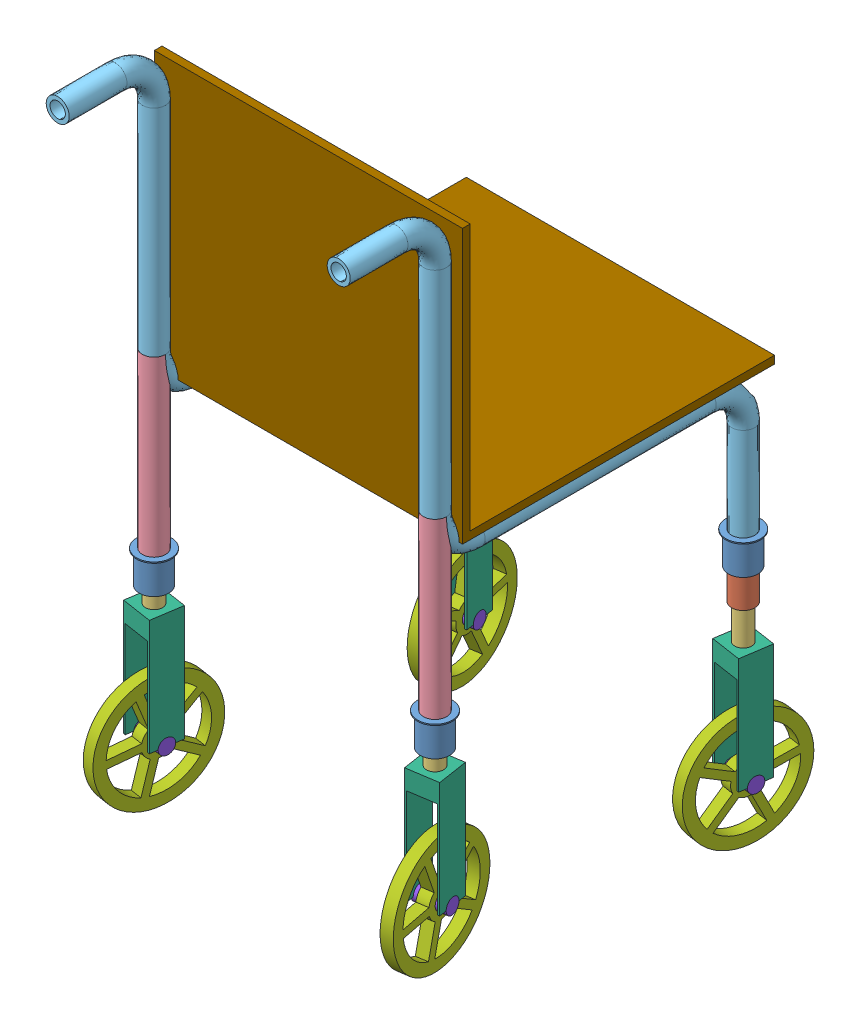
SolidWorks assembly telescope_copy_1, configuration Default. Lengths in mm.
Overall size (854.56 1888.19 1253.25).
33 component instances, 9 part files, 36 mates.
Components (placement in the parent):
- Part1-1: Part1 [Default] at (-1335.3167 235.5102 -102.0861) x (0 -1 0) z (-0.568138 0 -0.822933) size (83 90 90)
- Part2-1: Part2 [Default] at (-1335.3167 243.7286 -102.0861) x (0 -1 0) z (-0.866706 0 0.498819) size (83 70 70)
- Part3-1: Part3 [Default] at (-1335.3167 362.4799 -102.0861) x (0 -1 0) z (0.973036 0 -0.230654) size (120 54 54)
- fra-1: fra [Default] at (-1335.3167 757.6458 697.9139) size (60 450 60)
- frame-1: frame [Default] at (-1335.3167 657.4677 697.9139) size (60 1140 1080)
- Part3-2: Part3 [Default] at (-1335.3167 504.1743 697.9139) x (0 -1 0) z (-0.936287 0 0.351235) size (120 54 54)
- Part2-2: Part2 [Default] at (-1335.3167 310.8642 697.9139) x (0 -1 0) z (-0.866706 0 0.498819) size (83 70 70)
- Part1-2: Part1 [Default] at (-1335.3167 227.6458 697.9139) x (0 -1 0) z (-0.568138 0 -0.822933) size (83 90 90)
- rev-1: rev [Default] at (-1295.7832 34.1829 691.8227) x (-0.988337 0 0.152282) z (-0.152282 0 -0.988337) size (80 300 80)
- rev-2: rev [Default] at (-1295.7679 -87.4278 -96.0946) x (-0.988718 0 -0.149786) z (0.149786 0 -0.988718) size (80 300 80)
- wheel_fr-1: wheel_fr [Default] at (-1350.1417 -115.8171 700.1982) x (0.988337 0 -0.152282) z (0.095682 0.777955 0.620992) size (30 300 300)
- wheel_fr-2: wheel_fr [Default] at (-1320.4859 -237.4278 -99.8393) x (-0.988718 0 -0.149786) z (0.071254 0.879605 -0.470339) size (30 300 300)
- pin-1: pin [Default] at (-1335.3167 -115.8171 697.9139) x (0.988337 0 -0.152282) z (0.152282 0 0.988337) size (40 40 40)
- pin-2: pin [Default] at (-1374.8502 -115.8171 704.0052) x (0.988337 0 -0.152282) z (0.152282 0 0.988337) size (40 40 40)
- pin-3: pin [Default] at (-1335.3167 -237.4278 -102.0861) x (-0.988718 0 -0.149786) z (0.149786 0 -0.988718) size (40 40 40)
- pin-4: pin [Default] at (-1295.7679 -237.4278 -96.0946) x (-0.988718 0 -0.149786) z (0.130765 -0.487692 -0.863167) size (40 40 40)
- wheel_fr-3: wheel_fr [Default] at (-2049.8583 -115.8171 700.1982) x (-0.988337 0 -0.152282) z (0.095682 -0.777955 -0.620992) size (30 300 300)
- pin-5: pin [Default] at (-2064.6833 -115.8171 697.9139) x (-0.988337 0 -0.152282) z (0.152282 0 -0.988337) size (40 40 40)
- rev-3: rev [Default] at (-2104.2168 34.1829 691.8227) x (0.988337 0 0.152282) z (-0.152282 0 0.988337) size (80 300 80)
- pin-6: pin [Default] at (-2025.1498 -115.8171 704.0052) x (-0.988337 0 -0.152282) z (0.152282 0 -0.988337) size (40 40 40)
- Part3-3: Part3 [Default] at (-2064.6833 504.1743 697.9139) x (0 -1 0) z (-0.936287 0 -0.351235) size (120 54 54)
- Part2-3: Part2 [Default] at (-2064.6833 310.8642 697.9139) x (0 -1 0) z (-0.866706 0 -0.498819) size (83 70 70)
- Part1-3: Part1 [Default] at (-2064.6833 227.6458 697.9139) x (0 -1 0) z (-0.568138 0 0.822933) size (83 90 90)
- wheel_fr-4: wheel_fr [Default] at (-2079.5141 -237.4278 -99.8393) x (0.988718 0 -0.149786) z (0.071254 -0.879605 0.470339) size (30 300 300)
- pin-7: pin [Default] at (-2064.6833 -237.4278 -102.0861) x (0.988718 0 -0.149786) z (0.149786 0 0.988718) size (40 40 40)
- rev-4: rev [Default] at (-2104.2321 -87.4278 -96.0946) x (0.988718 0 -0.149786) z (0.149786 0 0.988718) size (80 300 80)
- pin-8: pin [Default] at (-2104.2321 -237.4278 -96.0946) x (0.988718 0 -0.149786) z (0.130765 0.487692 0.863167) size (40 40 40)
- Part3-4: Part3 [Default] at (-2064.6833 362.4799 -102.0861) x (0 -1 0) z (0.973036 0 0.230654) size (120 54 54)
- Part2-4: Part2 [Default] at (-2064.6833 243.7286 -102.0861) x (0 -1 0) z (-0.866706 0 -0.498819) size (83 70 70)
- Part1-4: Part1 [Default] at (-2064.6833 235.5102 -102.0861) x (0 -1 0) z (-0.568138 0 0.822933) size (83 90 90)
- frame-2: frame [Default] at (-2064.6833 657.4677 697.9139) size (60 1140 1080)
- fra-2: fra [Default] at (-2064.6833 757.6458 697.9139) x (-1 0 0) z (0 0 -1) size (60 450 60)
- seat-1: seat [Default] at (-2096.6499 693.4702 655.1963) size (800 710 810)
Mates (geometry in assembly coordinates):
- Concentric1: concentric anti-aligned: cylinder of Part1-1 through (-1335.3167 235.5102 -102.0861) axis (0 -1 0) radius 38; cylinder of Part2-1 through (-1335.3167 243.7286 -102.0861) axis (0 1 0) radius 30
- Concentric2: concentric aligned: cylinder of Part2-1 through (-1335.3167 243.7286 -102.0861) axis (0 1 0) radius 30; cylinder of Part3-1 through (-1335.3167 168.4799 -102.0861) axis (0 1 0) radius 22
- LimitDistance1: limit distance = 80 mm aligned: plane of Part2-1 through (-1321.8486 152.5102 -78.685) normal (0 -1 0); plane of Part1-1 through (-1364.1193 232.5102 -82.2012) normal (0 -1 0)
- Concentric3: concentric aligned: cylinder of Part2-1 through (-1335.3167 243.7286 -102.0861) axis (0 1 0) radius 30; cylinder of Part3-1 through (-1335.3167 168.4799 -102.0861) axis (0 1 0) radius 22
- LimitDistance4: limit distance = 3 mm aligned: plane of Part2-1 through (-1321.8486 152.5102 -78.685) normal (0 -1 0); plane of Part3-1 through (-1341.5444 155.5102 -128.358) normal (0 -1 0)
- Concentric4: concentric aligned: cylinder of fra-1 through (-1335.3167 757.6458 697.9139) axis (0 -1 0) radius 20; circle of frame-1
- Concentric5: concentric aligned: circle of fra-1; cylinder of frame-1 through (-1335.3167 1317.4677 697.9139) axis (0 -1 0) radius 30
- Concentric6: concentric aligned: circle of fra-1; circle of frame-1
- Concentric8: concentric aligned: circle of Part1-1; circle of frame-1
- Concentric9: concentric aligned: circle of Part1-1; circle of frame-1
- Concentric10: concentric aligned: cylinder of Part1-1 through (-1335.3167 235.5102 -102.0861) axis (0 -1 0) radius 38; cylinder of frame-1 through (-1335.3167 557.4677 -102.0861) axis (0 -1 0) radius 30
- LimitDistance5: limit distance = 77.5589 mm aligned: plane of Part2-2 through (-1321.8486 219.6458 721.315) normal (0 -1 0); plane of Part3-2 through (-1325.8334 297.2047 723.1937) normal (0 -1 0)
- LimitDistance6: limit distance = 5 mm aligned: plane of Part2-2 through (-1321.8486 219.6458 721.315) normal (0 -1 0); plane of Part1-2 through (-1364.1193 224.6458 717.7988) normal (0 -1 0)
- Concentric14: concentric anti-aligned: cylinder of Part2-2 through (-1335.3167 310.8642 697.9139) axis (0 1 0) radius 30; cylinder of Part1-2 through (-1335.3167 227.6458 697.9139) axis (0 -1 0) radius 38
- Concentric15: concentric aligned: cylinder of Part3-2 through (-1335.3167 310.1743 697.9139) axis (0 1 0) radius 22; cylinder of Part2-2 through (-1335.3167 310.8642 697.9139) axis (0 1 0) radius 30
- Concentric16: concentric aligned: cylinder of Part3-2 through (-1335.3167 310.1743 697.9139) axis (0 1 0) radius 22; cylinder of Part2-2 through (-1335.3167 310.8642 697.9139) axis (0 1 0) radius 30
- Concentric20: concentric aligned: circle of fra-1; circle of Part1-2
- Lock1: lock: unknown of fra-1; unknown of Part1-2
- Concentric22: concentric aligned: circle of Part3-2; circle of rev-1
- Lock2: lock: unknown of Part3-2; unknown of rev-1
- Concentric29: concentric aligned: circle of Part3-1; circle of rev-2
- Lock3: lock: unknown of Part3-1; unknown of rev-2
- Lock4: lock: unknown of fra-1; unknown of frame-1
- Coincident1: coincident anti-aligned: line of rev-1 through (-1300.7249 -115.8171 692.5841) axis (0.988337 0 -0.152282); line of wheel_fr-1 through (-1320.4916 -115.8171 695.6297) axis (-0.988337 0 0.152282)
- Distance1: distance = 20 mm anti-aligned: plane of wheel_fr-1 through (-1320.4916 -115.8171 695.6297) normal (0.988337 0 -0.152282); plane of rev-1 through (-1294.6336 134.1829 732.1176) normal (-0.988337 0 0.152282)
- Coincident3: coincident aligned: line of rev-2 through (-1374.8654 -237.4278 -108.0775) axis (0.988718 0 0.149786); line of wheel_fr-2 through (-1350.1475 -237.4278 -104.3328) axis (0.988718 0 0.149786)
- Distance2: distance = 20 mm anti-aligned: plane of wheel_fr-2 through (-1350.1475 -237.4278 -104.3328) normal (-0.988718 0 -0.149786); plane of rev-2 through (-1375.9133 12.5722 -67.7798) normal (0.988718 0 0.149786)
- Concentric30: concentric aligned: cylinder of wheel_fr-1 through (-1320.4916 -115.8171 695.6297) axis (-0.988337 0 0.152282) radius 20; cylinder of pin-1 through (-1295.7832 -115.8171 691.8227) axis (-0.988337 0 0.152282) radius 20
- Coincident5: coincident aligned: plane of rev-1 through (-1295.7832 -115.8171 691.8227) normal (0.988337 0 -0.152282); plane of pin-1 through (-1295.7832 -115.8171 691.8227) normal (0.988337 0 -0.152282)
- Concentric31: concentric aligned: cylinder of wheel_fr-1 through (-1320.4916 -115.8171 695.6297) axis (-0.988337 0 0.152282) radius 20; cylinder of pin-2 through (-1335.3167 -115.8171 697.9139) axis (-0.988337 0 0.152282) radius 20
- Coincident6: coincident aligned: plane of rev-1 through (-1374.8502 -115.8171 704.0052) normal (-0.988337 0 0.152282); plane of pin-2 through (-1374.8502 -115.8171 704.0052) normal (-0.988337 0 0.152282)
- Concentric32: concentric aligned: cylinder of wheel_fr-2 through (-1350.1475 -237.4278 -104.3328) axis (0.988718 0 0.149786) radius 20; cylinder of pin-3 through (-1374.8654 -237.4278 -108.0775) axis (0.988718 0 0.149786) radius 20
- Coincident7: coincident aligned: plane of rev-2 through (-1374.8654 -237.4278 -108.0775) normal (-0.988718 0 -0.149786); plane of pin-3 through (-1374.8654 -237.4278 -108.0775) normal (-0.988718 0 -0.149786)
- Concentric33: concentric aligned: cylinder of wheel_fr-2 through (-1350.1475 -237.4278 -104.3328) axis (0.988718 0 0.149786) radius 20; cylinder of pin-4 through (-1335.3167 -237.4278 -102.0861) axis (0.988718 0 0.149786) radius 20
- Coincident8: coincident aligned: plane of rev-2 through (-1295.7679 -237.4278 -96.0946) normal (0.988718 0 0.149786); plane of pin-4 through (-1295.7679 -237.4278 -96.0946) normal (0.988718 0 0.149786)
- GearMate1: gear = 80 : 80 mm: circle of wheel_fr-1; circle of wheel_fr-2
